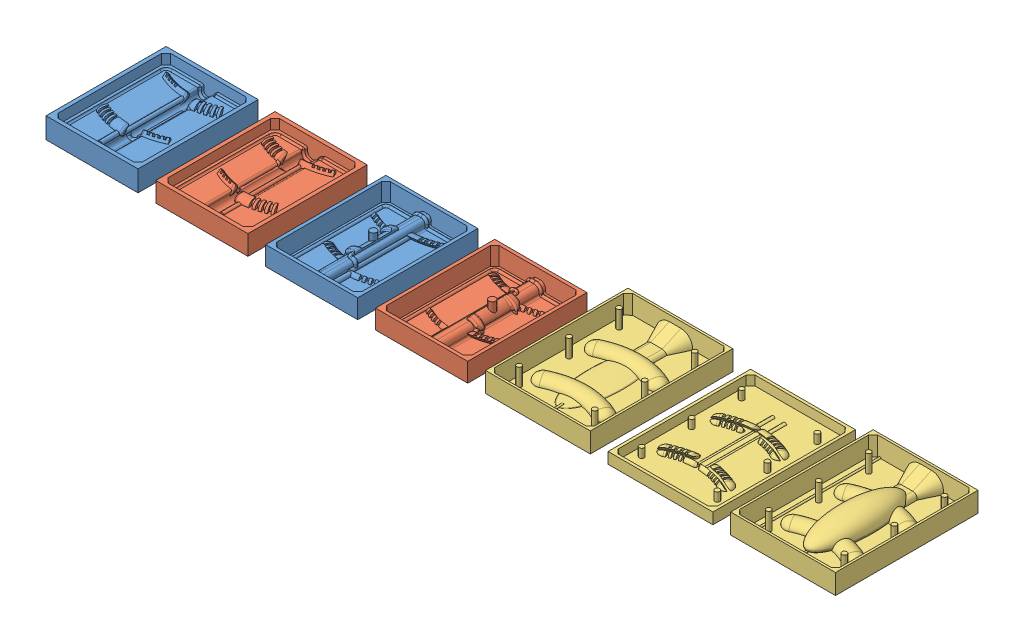
SolidWorks assembly printing_assembly, configuration Default. Lengths in mm.
Overall size (1127.84 36.24 203.58).
11 component instances, 6 part files, 29 mates.
Components (placement in the parent):
- makerbot_left-hand_bathtub_01-1: makerbot_left-hand_bathtub_01 [top_mold] at (-222.9859 3.175 -94.5274) size (131.46 27.18 171.59)
- makerbot_right-hand_bathtub_01-1: makerbot_right-hand_bathtub_01 [top] at (-65.7496 3.175 -94.5757) size (131.69 27.09 170.32)
- makerbot_left-hand_bathtub_01-2: makerbot_left-hand_bathtub_01 [bottom_mold] at (-536.5424 16.4645 -94.5274) x (-1 0 0) z (0 0 1) size (131.46 29.71 171.59)
- makerbot_right-hand_bathtub_01-2: makerbot_right-hand_bathtub_01 [bottom] at (-379.8782 14.8766 -94.5757) x (-1 0 0) z (0 0 1) size (131.69 28.12 170.32)
- makerbot_silicone_body_bathtubs_01-1: makerbot_silicone_body_bathtubs_01 [bottom surface] at (97.0931 3.175 -100.2011) x (1 0 0) z (0 0 -1) size (149.74 35.11 203.58)
- makerbot_silicone_body_bathtubs_01-2: makerbot_silicone_body_bathtubs_01 [bottom alignment] at (272.2299 3.175 -100.2011) x (1 0 0) z (0 0 -1) size (149.74 15.88 203.58)
- makerbot_silicone_body_bathtubs_01-3: makerbot_silicone_body_bathtubs_01 [top] at (453.7173 3.175 -100.2011) x (-1 0 0) z (0 0 -1) size (149.74 35.11 203.58)
- makerbot_build_volume-1: makerbot_build_volume [Default] at (101.6 10.5502 -63.877) x (0 0 1) z (-1 0 0) size (279.4 152.4 152.4) (hidden)
- makerbot_clamp_plate-1: makerbot_clamp_plate [Default] at (628.219 -25.4 -103.3759) x (-1 0 0) z (0 0 1) size (149.74 3.18 203.58) (hidden)
- makerbot_clamp_plate-2: makerbot_clamp_plate [Default] at (802.0858 -25.4 -103.3759) x (-1 0 0) z (0 0 1) size (149.74 3.18 203.58) (hidden)
- Part2^printing_assembly-1: Part2^printing_assembly [Default] at origin (virtual)
Mates (geometry in assembly coordinates):
- Coincident1: coincident anti-aligned: plane of makerbot_left-hand_bathtub_01-2 through (-536.5424 0 -94.5274) normal (0 -1 0); plane of assembly through (0 0 0) normal (0 1 0)
- Coincident2: coincident aligned: plane of makerbot_left-hand_bathtub_01-2 through (-470.9781 -1.1931 0) normal (0 0 1); plane of assembly through (0 0 0) normal (0 0 1)
- Coincident3: coincident anti-aligned: plane of makerbot_right-hand_bathtub_01-2 through (-379.8782 0 -94.5757) normal (0 -1 0); plane of assembly through (0 0 0) normal (0 1 0)
- Coincident4: coincident aligned: line of makerbot_right-hand_bathtub_01-2 through (-313.933 28.1179 0) axis (-1 0 0); plane of assembly
- Coincident5: coincident anti-aligned: plane of makerbot_left-hand_bathtub_01-1 through (-222.9859 0 -94.5274) normal (0 -1 0); plane of assembly through (0 0 0) normal (0 1 0)
- Coincident6: coincident aligned: plane of makerbot_left-hand_bathtub_01-1 through (-288.5502 20.8326 0) normal (0 0 1); plane of assembly through (0 0 0) normal (0 0 1)
- Coincident7: coincident aligned: plane of makerbot_right-hand_bathtub_01-1 through (-131.6947 20.7414 0) normal (0 0 1); plane of assembly through (0 0 0) normal (0 0 1)
- Coincident8: coincident anti-aligned: plane of makerbot_right-hand_bathtub_01-1 through (-65.7496 0 -94.5757) normal (0 -1 0); plane of assembly through (0 0 0) normal (0 1 0)
- Distance1: distance = 25.4 mm: line of makerbot_left-hand_bathtub_01-2 through (-470.9781 29.7054 -171.5927) axis (0 0 1); line of makerbot_right-hand_bathtub_01-2 through (-445.6277 28.1179 0) axis (0 0 -1)
- Distance2: distance = 25.4 mm: line of makerbot_right-hand_bathtub_01-2 through (-313.933 28.1179 -170.3241) axis (0 0 1); line of makerbot_left-hand_bathtub_01-1 through (-288.5502 27.1826 0) axis (0 0 -1)
- Distance3: distance = 25.4 mm: line of makerbot_left-hand_bathtub_01-1 through (-157.0945 27.1826 -171.5927) axis (0 0 1); line of makerbot_right-hand_bathtub_01-1 through (-131.6947 27.0914 -170.3241) axis (0 0 1)
- Coincident12: coincident: line of makerbot_right-hand_bathtub_01-1 through (0 27.0914 0) axis (0 0 -1); plane of assembly
- Coincident13: coincident anti-aligned: plane of makerbot_silicone_body_bathtubs_01-3 through (453.7173 0 -100.2011) normal (0 -1 0); plane of assembly through (0 0 0) normal (0 1 0)
- Coincident14: coincident anti-aligned: plane of makerbot_silicone_body_bathtubs_01-1 through (97.0931 0 -100.2011) normal (0 -1 0); plane of assembly through (0 0 0) normal (0 1 0)
- Coincident15: coincident anti-aligned: plane of makerbot_silicone_body_bathtubs_01-2 through (272.2299 0 -100.2011) normal (0 -1 0); plane of assembly through (0 0 0) normal (0 1 0)
- Coincident16: coincident aligned: plane of makerbot_silicone_body_bathtubs_01-1 through (25.4 28.575 0) normal (0 0 1); plane of assembly through (0 0 0) normal (0 0 1)
- Distance4: distance = 25.4 mm anti-aligned: plane of makerbot_silicone_body_bathtubs_01-1 through (25.4 28.575 0) normal (-1 0 0); plane of makerbot_right-hand_bathtub_01-1 through (0 20.7414 -170.3241) normal (1 0 0)
- Coincident18: coincident aligned: plane of makerbot_silicone_body_bathtubs_01-2 through (350.2736 28.575 0) normal (0 0 1); plane of assembly through (0 0 0) normal (0 0 1)
- Distance5: distance = 25.4 mm anti-aligned: plane of makerbot_silicone_body_bathtubs_01-2 through (200.5368 28.575 -203.577) normal (-1 0 0); plane of makerbot_silicone_body_bathtubs_01-1 through (175.1368 28.575 0) normal (1 0 0)
- Coincident20: coincident aligned: plane of makerbot_silicone_body_bathtubs_01-3 through (525.4104 28.575 0) normal (0 0 1); plane of assembly through (0 0 0) normal (0 0 1)
- Distance6: distance = 25.4 mm anti-aligned: plane of makerbot_silicone_body_bathtubs_01-2 through (350.2736 28.575 -203.577) normal (1 0 0); plane of makerbot_silicone_body_bathtubs_01-3 through (375.6736 28.575 -203.577) normal (-1 0 0)
- Coincident23: coincident aligned: line of makerbot_silicone_body_bathtubs_01-1 through (25.4 28.575 -203.577) axis (0 -1 0); line of makerbot_build_volume-1 through (25.4 86.7502 -203.577) axis (0 -1 0)
- Parallel1: parallel anti-aligned: plane of makerbot_silicone_body_bathtubs_01-1 through (25.4 28.575 0) normal (0 0 1); plane of makerbot_build_volume-1 through (177.8 86.7502 -203.577) normal (0 0 -1)
- Coincident26: coincident anti-aligned: plane of makerbot_clamp_plate-1 through (628.219 0 -103.3759) normal (0 -1 0); plane of assembly through (0 0 0) normal (0 1 0)
- Coincident28: coincident aligned: plane of makerbot_clamp_plate-1 through (693.5622 3.175 0) normal (0 0 1); plane of assembly through (0 0 0) normal (0 0 1)
- Distance7: distance = 25.4 mm: line of makerbot_clamp_plate-1 through (550.8104 3.175 -196.964) axis (0 0 1); plane of makerbot_silicone_body_bathtubs_01-3 through (525.4104 28.575 -203.577) normal (1 0 0)
- Coincident30: coincident anti-aligned: plane of makerbot_clamp_plate-2 through (802.0858 0 -103.3759) normal (0 -1 0); plane of assembly through (0 0 0) normal (0 1 0)
- Coincident31: coincident aligned: plane of makerbot_clamp_plate-2 through (867.4289 3.175 0) normal (0 0 1); plane of assembly through (0 0 0) normal (0 0 1)
- Distance8: distance = 25.4 mm: line of makerbot_clamp_plate-2 through (724.6772 3.175 -196.964) axis (0 0 1); line of makerbot_clamp_plate-1 through (699.2772 3.175 -6.613) axis (0 0 -1)
